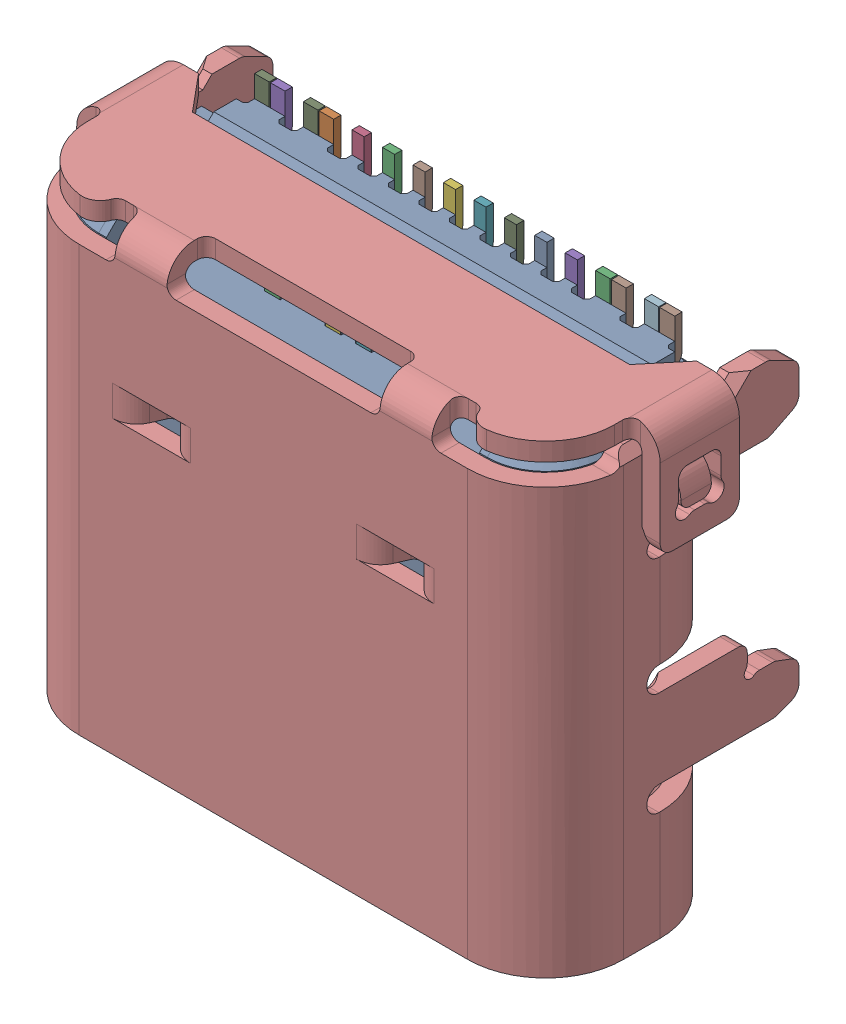
SolidWorks assembly Type_C1, configuration Default. Lengths in mm.
Overall size (9.58 7.71 4.16).
23 component instances, 22 part files, 0 mates.
Components (placement in the parent):
- 698b116-264-211_1-1: 698b116-264-211_1 [Default] at (13.8229 -5.1877 -11.5) x (1 0 0) z (0 -1 0) size (9.58 4.16 7.71)
  - SOLID-1: SOLID [Default] at origin size (8.34 3.56 7.05)
  - SOLID (1)-1: SOLID (1) [Default] at origin size (0.26 1.45 0.87)
  - SOLID (2)-1: SOLID (2) [Default] at origin size (0.26 1.45 0.87)
  - SOLID (3)-1: SOLID (3) [Default] at origin size (0.25 1.45 0.87)
  - SOLID (4)-1: SOLID (4) [Default] at origin size (0.25 1.45 0.87)
  - SOLID (5)-1: SOLID (5) [Default] at origin size (0.25 2.03 6.58)
  - SOLID (6)-1: SOLID (6) [Default] at origin size (0.25 2.03 6.58)
  - SOLID (7)-1: SOLID (7) [Default] at origin size (0.25 1.57 6.58)
  - SOLID (8)-1: SOLID (8) [Default] at origin size (0.25 1.57 6.58)
  - SOLID (9)-1: SOLID (9) [Default] at origin size (0.25 0.24 5.71)
  - SOLID (10)-1: SOLID (10) [Default] at origin size (0.25 0.24 5.71)
  - SOLID (11)-1: SOLID (11) [Default] at origin size (0.85 1.57 7.13)
  - SOLID (12)-1: SOLID (12) [Default] at origin size (0.35 2.03 6.78)
  - SOLID (13)-1: SOLID (13) [Default] at origin size (0.35 0.24 5.91)
  - SOLID (14)-1: SOLID (14) [Default] at origin size (0.35 2.03 6.78)
  - SOLID (15)-1: SOLID (15) [Default] at origin size (0.35 0.24 5.91)
  - SOLID (16)-1: SOLID (16) [Default] at origin size (0.85 1.57 7.13)
  - SOLID (17)-1: SOLID (17) [Default] at origin size (0.25 0.24 4.21)
  - SOLID (18)-1: SOLID (18) [Default] at origin size (0.25 0.24 4.21)
  - SOLID (19)-1: SOLID (19) [Default] at origin size (1.11 2.03 7.13)
  - SOLID (20)-1: SOLID (20) [Default] at origin size (1.12 2.03 7.13)
  - SOLID (21)-1: SOLID (21) [Default] at origin size (9.58 4.16 7.53)
